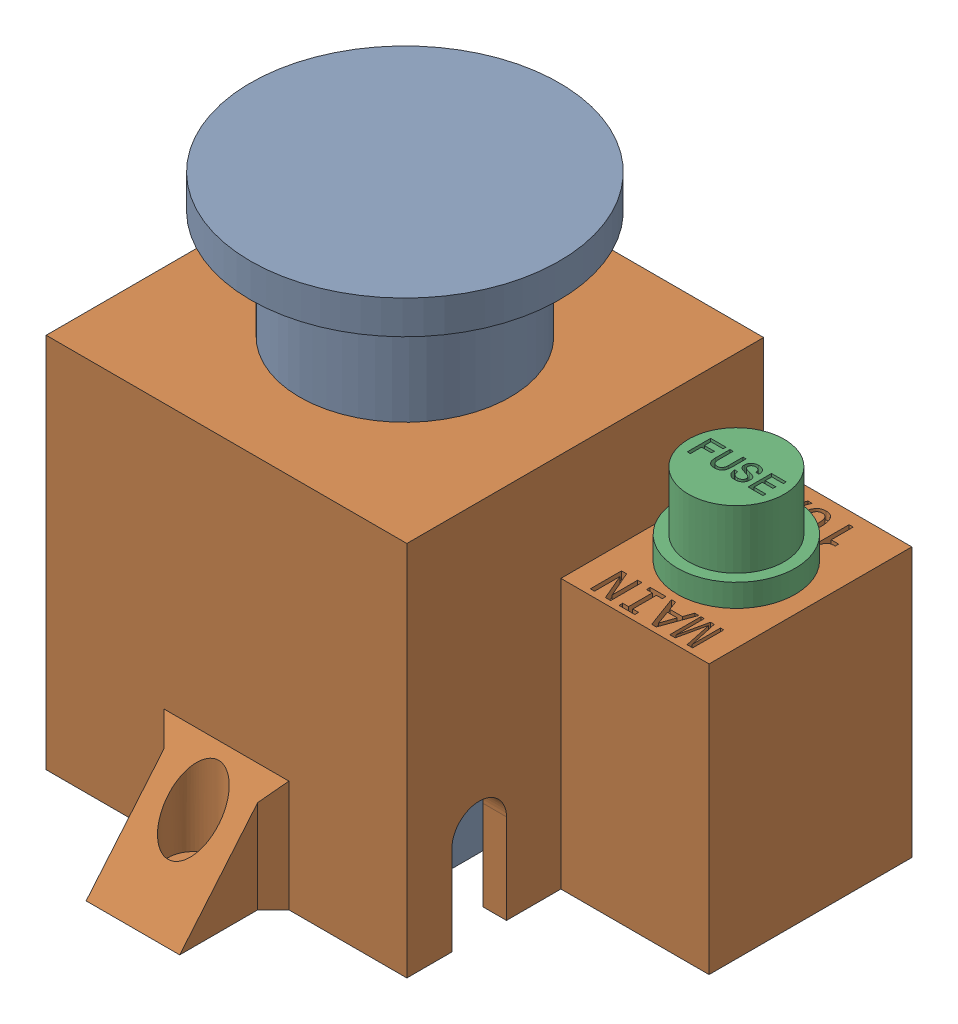
SolidWorks assembly eStopAsm_V2.5, configuration Default. Lengths in mm.
Overall size (77 66.5 57.75).
3 component instances, 3 part files, 6 mates.
Components (placement in the parent):
- eStop_V2-1: eStop_V2 [Default] at origin size (39.6 64.5 39.6)
- estopBracket_V2.5-2: estopBracket_V2.5 [Default] at (0 -2 0) size (77 48.25 57.75)
- fuse-1: fuse [Default] at (32.625 25.05 -9.875) size (15.1 38.9 16.51)
Mates (geometry in assembly coordinates):
- Concentric1: concentric anti-aligned: cylinder of eStop_V2-1 through (0 46.25 0) axis (0 -1 0) radius 10.875; cylinder of estopBracket_V2.5-2 through (0 -2 0) axis (0 1 0) radius 11.15
- Width1: width aligned: plane of estopBracket_V2.5-2 through (0 46.25 0) normal (0 1 0); plane of eStop_V2-1 through (0 40.75 0) normal (0 -1 0); plane of estopBracket_V2.5-2 through (0 46.25 0) normal (0 -1 0); plane of eStop_V2-1 through (0 40.75 0) normal (0 1 0)
- Parallel1: parallel anti-aligned: plane of eStop_V2-1 through (14.875 33.75 -18.125) normal (0 0 -1); plane of estopBracket_V2.5-2 through (20.125 40.75 -19.875) normal (0 0 1)
- Concentric2: concentric anti-aligned: cylinder of estopBracket_V2.5-2 through (32.625 28 -9.875) axis (0 1 0) radius 5.875; cylinder of fuse-1 through (32.625 32.75 -9.875) axis (0 -1 0) radius 5.75
- Width2: width aligned: plane of fuse-1 through (32.625 27.75 -9.875) normal (0 1 0); plane of estopBracket_V2.5-2 through (32.625 32.75 -9.875) normal (0 -1 0); plane of fuse-1 through (0 32.5 0) normal (0 1 0); plane of estopBracket_V2.5-2 through (0 28 0) normal (0 -1 0)
- Parallel2: parallel aligned: plane of eStop_V2-1 through (14.875 33.75 -18.125) normal (0 0 -1); plane of fuse-1 through (30.625 4.25 -10.075) normal (0 0 -1)
